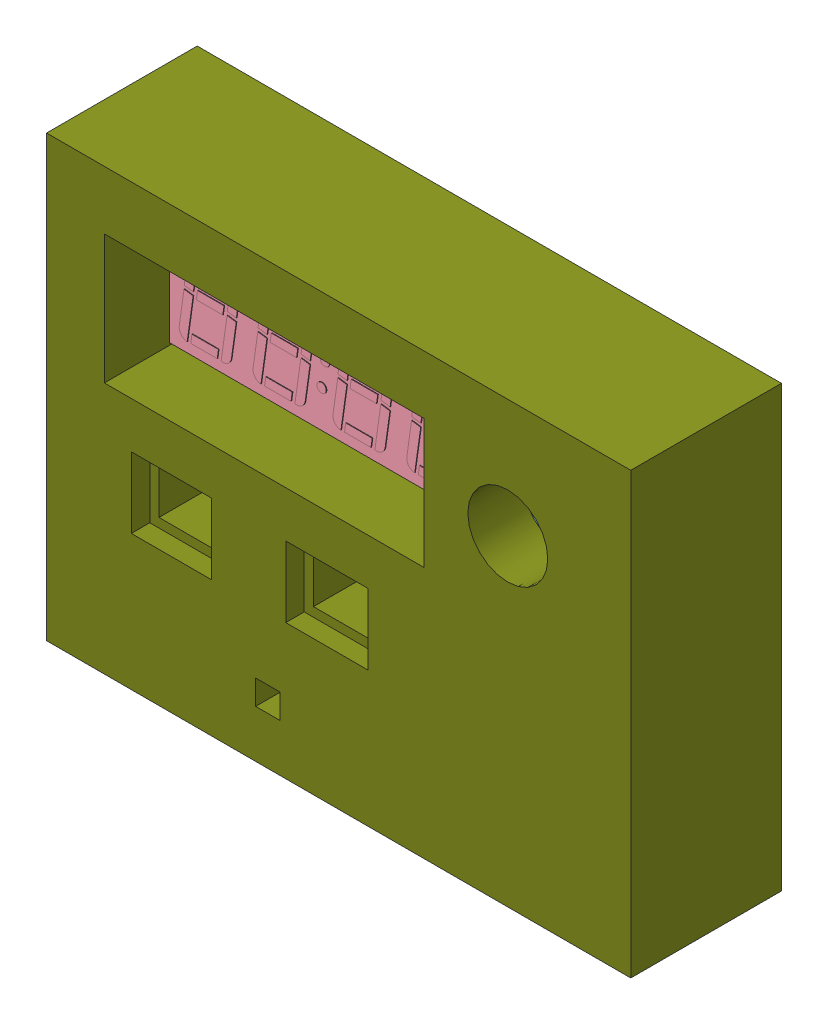
SolidWorks assembly phase-b-pcb-in-enclosure, configuration Default. Lengths in mm.
Overall size (95 71.5 24.5).
94 component instances, 17 part files, 4 mates.
Components (placement in the parent):
- phase-b-PCB-3D-model.STEP-1: phase-b-PCB-3D-model.STEP [Default] at (-85.1455 131.03 64.8187) size (83.95 61.34 16.53)
  - C_0603_1608Metric.STEP-1: C_0603_1608Metric.STEP [Default] at (82.169 -111.059 1.63) x (0 -1 0) z (0 0 1) size (1.6 0.8 0.8)
    - SOLID.STEP-1: SOLID.STEP [Default] at origin size (1.6 0.8 0.8)
  - Crystal_SMD_Abracon_ABM8G-4Pin_3.2x2.5mm.STEP-1: Crystal_SMD_Abracon_ABM8G-4Pin_3.2x2.5mm.STEP [Default] at (133.731 -81.827 1.63) size (3.2 2.5 0.64)
    - SOLID-0.STEP-1: SOLID-0.STEP [Default] at origin size (3.2 2.5 0.64)
  - R_0805_2012Metric.STEP-1: R_0805_2012Metric.STEP [Default] at (111.506 -117.885 1.63) x (-1 0 0) z (0 0 1) size (2 1.2 0.45)
    - SOLID-1.STEP-1: SOLID-1.STEP [Default] at origin size (2 1.2 0.45)
  - R_0805_2012Metric.STEP-2: R_0805_2012Metric.STEP [Default] at (111.506 -115.951 1.63) x (-1 0 0) z (0 0 1) size (2 1.2 0.45)
    - SOLID-1.STEP-1: SOLID-1.STEP [Default] at origin size (2 1.2 0.45)
  - CA56-12EWA.STEP-1: CA56-12EWA.STEP [Default] at (107.442 -65.278 1.63) x (0 -1 0) z (0 0 1) size (19 50.3 12.2)
    - SOLID-2.STEP-1: SOLID-2.STEP [Default] at origin size (19 50.3 12.2)
  - Buzzer_12x9.5RM7.6.STEP-1: Buzzer_12x9.5RM7.6.STEP [Default] at (136.535 -72.771 1.63) size (12 12 12.53)
    - SOLID-3.STEP-1: SOLID-3.STEP [Default] at origin size (12 12 12.53)
  - SOT-23-5.STEP-1: SOT-23-5.STEP [Default] at (85.344 -111.125 1.63) size (2.8 2.9 1.55)
    - SOLID-4.STEP-1: SOLID-4.STEP [Default] at origin size (2.8 2.9 1.55)
  - R_0805_2012Metric.STEP-3: R_0805_2012Metric.STEP [Default] at (111.506 -111.887 1.63) x (-1 0 0) z (0 0 1) size (2 1.2 0.45)
    - SOLID-1.STEP-1: SOLID-1.STEP [Default] at origin size (2 1.2 0.45)
  - PinSocket_2x04_P2.54mm_Vertical.STEP-1: PinSocket_2x04_P2.54mm_Vertical.STEP [Default] at (76.855 -106.563 1.63) size (5.08 10.16 10.1)
    - SOLID-5.STEP-1: SOLID-5.STEP [Default] at origin size (5.08 10.16 10.1)
  - C_0603_1608Metric.STEP-2: C_0603_1608Metric.STEP [Default] at (85.8465 -108.585 1.63) x (-1 0 0) z (0 0 1) size (1.6 0.8 0.8)
    - SOLID.STEP-1: SOLID.STEP [Default] at origin size (1.6 0.8 0.8)
  - C_0603_1608Metric.STEP-3: C_0603_1608Metric.STEP [Default] at (142.494 -98.298 1.63) size (1.6 0.8 0.8)
    - SOLID.STEP-1: SOLID.STEP [Default] at origin size (1.6 0.8 0.8)
  - C_0603_1608Metric.STEP-4: C_0603_1608Metric.STEP [Default] at (141.859 -95.123 1.63) size (1.6 0.8 0.8)
    - SOLID.STEP-1: SOLID.STEP [Default] at origin size (1.6 0.8 0.8)
  - R_0603_1608Metric.STEP-1: R_0603_1608Metric.STEP [Default] at (79.375 -110.744 1.63) x (0 -1 0) z (0 0 1) size (1.6 0.8 0.45)
    - SOLID-6.STEP-1: SOLID-6.STEP [Default] at origin size (1.6 0.8 0.45)
  - TQFP-44_10x10mm_P0.8mm.STEP-1: TQFP-44_10x10mm_P0.8mm.STEP [Default] at (133.223 -94.996 1.63) x (-1 0 0) z (0 0 1) size (12 12 1.1)
    - SOLID-7.STEP-1: SOLID-7.STEP [Default] at origin size (12 12 1.1)
  - C_0603_1608Metric.STEP-5: C_0603_1608Metric.STEP [Default] at (141.859 -93.599 1.63) size (1.6 0.8 0.8)
    - SOLID.STEP-1: SOLID.STEP [Default] at origin size (1.6 0.8 0.8)
  - R_0805_2012Metric.STEP-4: R_0805_2012Metric.STEP [Default] at (124.46 -109.474 1.63) size (2 1.2 0.45)
    - SOLID-1.STEP-1: SOLID-1.STEP [Default] at origin size (2 1.2 0.45)
  - R_0603_1608Metric.STEP-2: R_0603_1608Metric.STEP [Default] at (118.999 -88.138 1.63) size (1.6 0.8 0.45)
    - SOLID-6.STEP-1: SOLID-6.STEP [Default] at origin size (1.6 0.8 0.45)
  - LED_0805_2012Metric.STEP-1: LED_0805_2012Metric.STEP [Default] at (85.1685 -86.36 1.63) size (2 1.25 1.1)
    - SOLID-8.STEP-1: SOLID-8.STEP [Default] at origin size (2 1.25 1.1)
  - R_0603_1608Metric.STEP-3: R_0603_1608Metric.STEP [Default] at (99.949 -94.869 1.63) x (0 -1 0) z (0 0 1) size (1.6 0.8 0.45)
    - SOLID-6.STEP-1: SOLID-6.STEP [Default] at origin size (1.6 0.8 0.45)
  - C_0603_1608Metric.STEP-6: C_0603_1608Metric.STEP [Default] at (135.636 -103.505 1.63) x (0 -1 0) z (0 0 1) size (1.6 0.8 0.8)
    - SOLID.STEP-1: SOLID.STEP [Default] at origin size (1.6 0.8 0.8)
  - PinSocket_2x03_P2.54mm_Vertical.STEP-1: PinSocket_2x03_P2.54mm_Vertical.STEP [Default] at (146.979 -81.93 1.63) x (-1 0 0) z (0 0 -1) size (5.08 7.62 10.1)
    - SOLID-9.STEP-1: SOLID-9.STEP [Default] at origin size (5.08 7.62 10.1)
  - SOT-23-6.STEP-1: SOT-23-6.STEP [Default] at (146.68 -102.557 1.63) x (0 1 0) z (0 0 1) size (2.8 2.9 1.55)
    - SOLID-10.STEP-1: SOLID-10.STEP [Default] at origin size (2.8 2.9 1.55)
  - R_0805_2012Metric.STEP-5: R_0805_2012Metric.STEP [Default] at (88.5425 -86.36 1.63) x (-1 0 0) z (0 0 1) size (2 1.2 0.45)
    - SOLID-1.STEP-1: SOLID-1.STEP [Default] at origin size (2 1.2 0.45)
  - C_0603_1608Metric.STEP-7: C_0603_1608Metric.STEP [Default] at (88.2595 -111.313 1.63) x (0 1 0) z (0 0 1) size (1.6 0.8 0.8)
    - SOLID.STEP-1: SOLID.STEP [Default] at origin size (1.6 0.8 0.8)
  - C_0603_1608Metric.STEP-8: C_0603_1608Metric.STEP [Default] at (128.016 -102.616 1.63) x (-1 0 0) z (0 0 1) size (1.6 0.8 0.8)
    - SOLID.STEP-1: SOLID.STEP [Default] at origin size (1.6 0.8 0.8)
  - LED_0805_2012Metric.STEP-2: LED_0805_2012Metric.STEP [Default] at (139.187 -115.384 1.63) x (0 1 0) z (0 0 1) size (2 1.25 1.1)
    - SOLID-8.STEP-1: SOLID-8.STEP [Default] at origin size (2 1.25 1.1)
  - C_0603_1608Metric.STEP-9: C_0603_1608Metric.STEP [Default] at (124.333 -107.696 1.63) size (1.6 0.8 0.8)
    - SOLID.STEP-1: SOLID.STEP [Default] at origin size (1.6 0.8 0.8)
  - C_0603_1608Metric.STEP-10: C_0603_1608Metric.STEP [Default] at (135.636 -86.474 1.63) x (0 1 0) z (0 0 1) size (1.6 0.8 0.8)
    - SOLID.STEP-1: SOLID.STEP [Default] at origin size (1.6 0.8 0.8)
  - LED_0805_2012Metric.STEP-3: LED_0805_2012Metric.STEP [Default] at (93.4595 -86.36 1.63) size (2 1.25 1.1)
    - SOLID-8.STEP-1: SOLID-8.STEP [Default] at origin size (2 1.25 1.1)
  - R_0603_1608Metric.STEP-4: R_0603_1608Metric.STEP [Default] at (147.32 -107.252 1.63) x (0 1 0) z (0 0 1) size (1.6 0.8 0.45)
    - SOLID-6.STEP-1: SOLID-6.STEP [Default] at origin size (1.6 0.8 0.45)
  - R_0805_2012Metric.STEP-6: R_0805_2012Metric.STEP [Default] at (96.901 -86.36 1.63) x (-1 0 0) z (0 0 1) size (2 1.2 0.45)
    - SOLID-1.STEP-1: SOLID-1.STEP [Default] at origin size (2 1.2 0.45)
  - R_0603_1608Metric.STEP-5: R_0603_1608Metric.STEP [Default] at (95.7895 -111.379 1.63) x (0 -1 0) z (0 0 1) size (1.6 0.8 0.45)
    - SOLID-6.STEP-1: SOLID-6.STEP [Default] at origin size (1.6 0.8 0.45)
  - C_0603_1608Metric.STEP-11: C_0603_1608Metric.STEP [Default] at (124.333 -91.948 1.63) x (-1 0 0) z (0 0 1) size (1.6 0.8 0.8)
    - SOLID.STEP-1: SOLID.STEP [Default] at origin size (1.6 0.8 0.8)
  - R_0805_2012Metric.STEP-7: R_0805_2012Metric.STEP [Default] at (111.4025 -107.823 1.63) x (-1 0 0) z (0 0 1) size (2 1.2 0.45)
    - SOLID-1.STEP-1: SOLID-1.STEP [Default] at origin size (2 1.2 0.45)
  - C_0603_1608Metric.STEP-12: C_0603_1608Metric.STEP [Default] at (130.683 -81.827 1.63) x (0 1 0) z (0 0 1) size (1.6 0.8 0.8)
    - SOLID.STEP-1: SOLID.STEP [Default] at origin size (1.6 0.8 0.8)
  - R_0805_2012Metric.STEP-8: R_0805_2012Metric.STEP [Default] at (139.187 -112.023 1.63) x (0 -1 0) z (0 0 1) size (2 1.2 0.45)
    - SOLID-1.STEP-1: SOLID-1.STEP [Default] at origin size (2 1.2 0.45)
  - C_0603_1608Metric.STEP-13: C_0603_1608Metric.STEP [Default] at (138.557 -102.616 1.63) size (1.6 0.8 0.8)
    - SOLID.STEP-1: SOLID.STEP [Default] at origin size (1.6 0.8 0.8)
  - C_0603_1608Metric.STEP-14: C_0603_1608Metric.STEP [Default] at (131.699 -108.585 1.63) x (0 -1 0) z (0 0 1) size (1.6 0.8 0.8)
    - SOLID.STEP-1: SOLID.STEP [Default] at origin size (1.6 0.8 0.8)
  - R_0805_2012Metric.STEP-9: R_0805_2012Metric.STEP [Default] at (111.4025 -109.855 1.63) x (-1 0 0) z (0 0 1) size (2 1.2 0.45)
    - SOLID-1.STEP-1: SOLID-1.STEP [Default] at origin size (2 1.2 0.45)
  - TSSOP-16_4.4x5mm_P0.65mm.STEP-1: TSSOP-16_4.4x5mm_P0.65mm.STEP [Default] at (118.364 -110.871 1.63) size (6.4 5 1.1)
    - SOLID-11.STEP-1: SOLID-11.STEP [Default] at origin size (6.4 5 1.1)
  - R_0805_2012Metric.STEP-10: R_0805_2012Metric.STEP [Default] at (111.4025 -105.791 1.63) x (-1 0 0) z (0 0 1) size (2 1.2 0.45)
    - SOLID-1.STEP-1: SOLID-1.STEP [Default] at origin size (2 1.2 0.45)
  - USB_Mini-B_Lumberg_2486_01_Horizontal.STEP-1: USB_Mini-B_Lumberg_2486_01_Horizontal.STEP [Default] at (146.807 -113.352 1.63) size (9.9 9.21 5)
    - SOLID-12.STEP-1: SOLID-12.STEP [Default] at origin size (9.9 9.21 5)
  - R_0805_2012Metric.STEP-11: R_0805_2012Metric.STEP [Default] at (111.506 -113.919 1.63) x (-1 0 0) z (0 0 1) size (2 1.2 0.45)
    - SOLID-1.STEP-1: SOLID-1.STEP [Default] at origin size (2 1.2 0.45)
  - R_0603_1608Metric.STEP-6: R_0603_1608Metric.STEP [Default] at (145.796 -107.252 1.63) x (0 1 0) z (0 0 1) size (1.6 0.8 0.45)
    - SOLID-6.STEP-1: SOLID-6.STEP [Default] at origin size (1.6 0.8 0.45)
  - C_0603_1608Metric.STEP-15: C_0603_1608Metric.STEP [Default] at (136.779 -81.827 1.63) x (0 -1 0) z (0 0 1) size (1.6 0.8 0.8)
    - SOLID.STEP-1: SOLID.STEP [Default] at origin size (1.6 0.8 0.8)
  - PCB.STEP-1: PCB.STEP [Default] at origin size (83.95 61.34 1.58)
- phase-b-enclosure-v2-1: phase-b-enclosure-v2 [Default] at (27.1895 41.759 80.8987) x (1 0 0) z (0 -1 0) size (95 24.5 71.5)
- esp8266-module-rough-outline-1: esp8266-module-rough-outline [Default] at (-12.1005 27.918 76.3443) x (1 0 0) z (0 1 0) size (24.38 5.61 14.5)
Mates (geometry in assembly coordinates):
- Concentric3: concentric aligned: cylinder of phase-b-PCB-3D-model.STEP-1/Buzzer_12x9.5RM7.6.STEP-1/SOLID-3.STEP-1 through (55.1895 58.259 66.4787) axis (0 0 -1) radius 6; cylinder of phase-b-enclosure-v2-1 through (55.1895 58.259 83.8987) axis (0 0 -1) radius 6.5
- Coincident2: coincident anti-aligned: plane of phase-b-PCB-3D-model.STEP-1/PinSocket_2x04_P2.54mm_Vertical.STEP-1/SOLID-5.STEP-1 through (-7.0205 15.577 73.4487) normal (0 0 1); plane of esp8266-module-rough-outline-1 through (-12.1005 27.918 73.4487) normal (0 0 -1)
- Coincident3: coincident aligned: plane of phase-b-PCB-3D-model.STEP-1/PinSocket_2x04_P2.54mm_Vertical.STEP-1/SOLID-5.STEP-1 through (-12.1005 25.737 66.4487) normal (-1 0 0); plane of esp8266-module-rough-outline-1 through (-12.1005 27.918 75.6585) normal (-1 0 0)
- Coincident4: coincident aligned: plane of phase-b-PCB-3D-model.STEP-1/PinSocket_2x04_P2.54mm_Vertical.STEP-1/SOLID-5.STEP-1 through (-12.1005 15.577 66.4487) normal (0 -1 0); plane of esp8266-module-rough-outline-1 through (-12.1005 15.577 73.4487) normal (0 -1 0)
